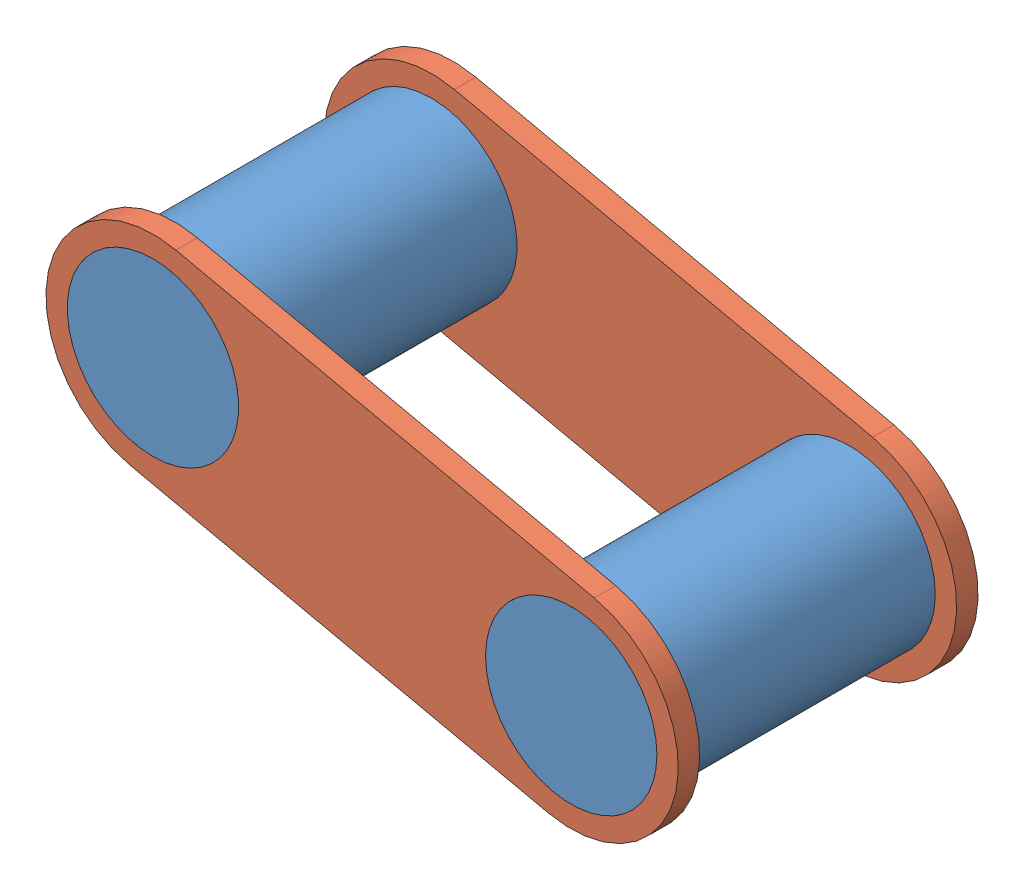
SolidWorks assembly LargeLinkageChain, configuration Default. Lengths in mm.
Overall size (39.94 20.59 17.78).
4 component instances, 2 part files, 8 mates.
Components (placement in the parent):
- LargeLinkCylinder-3: LargeLinkCylinder [Default] at (9.0301 0.4096 -27.24) size (10.16 10.16 17.78)
- LargeLinkCylinder-4: LargeLinkCylinder [Default] at (-22.7935 -2.2602 -27.24) x (0.146196 -0.989256 0) z (0 0 1) size (10.16 10.16 17.78)
- LinkagePart-3: LinkagePart [Default] at (70.1186 44.4805 -10.73) x (0.976612 -0.215008 0) z (0 0 1) size (38.1 12.7 1.27)
- LinkagePart-4: LinkagePart [Default] at (70.1186 44.4805 -27.24) x (0.976612 -0.215008 0) z (0 0 1) size (38.1 12.7 1.27)
Mates (geometry in assembly coordinates):
- Concentric1: concentric aligned: cylinder of LargeLinkCylinder-3 through (0.8108 0.4096 -9.46) axis (0 0 -1) radius 5.08; cylinder of LinkagePart-3 through (0.8108 0.4096 -9.46) axis (0 0 -1) radius 5.08
- Coincident1: coincident aligned: plane of LargeLinkCylinder-3 through (0.8108 0.4096 -9.46) normal (0 0 1); plane of LinkagePart-3 through (-23.9951 5.8708 -9.46) normal (0 0 1)
- Coincident2: coincident aligned: plane of LargeLinkCylinder-4 through (-23.9951 5.8708 -9.46) normal (0 0 1); plane of LinkagePart-3 through (-23.9951 5.8708 -9.46) normal (0 0 1)
- Concentric2: concentric aligned: cylinder of LargeLinkCylinder-4 through (-23.9951 5.8708 -9.46) axis (0 0 -1) radius 5.08; cylinder of LinkagePart-3 through (-23.9951 5.8708 -9.46) axis (0 0 -1) radius 5.08
- Concentric3: concentric aligned: cylinder of LargeLinkCylinder-3 through (0.8108 0.4096 -9.46) axis (0 0 -1) radius 5.08; cylinder of LinkagePart-4 through (0.8108 0.4096 -25.97) axis (0 0 -1) radius 5.08
- Coincident3: coincident aligned: plane of LargeLinkCylinder-3 through (0.8108 0.4096 -27.24) normal (0 0 -1); plane of LinkagePart-4 through (-23.9951 5.8708 -27.24) normal (0 0 -1)
- Coincident4: coincident aligned: plane of LargeLinkCylinder-4 through (-23.9951 5.8708 -27.24) normal (0 0 -1); plane of LinkagePart-4 through (-23.9951 5.8708 -27.24) normal (0 0 -1)
- Concentric4: concentric aligned: cylinder of LargeLinkCylinder-4 through (-23.9951 5.8708 -9.46) axis (0 0 -1) radius 5.08; cylinder of LinkagePart-4 through (-23.9951 5.8708 -25.97) axis (0 0 -1) radius 5.08
